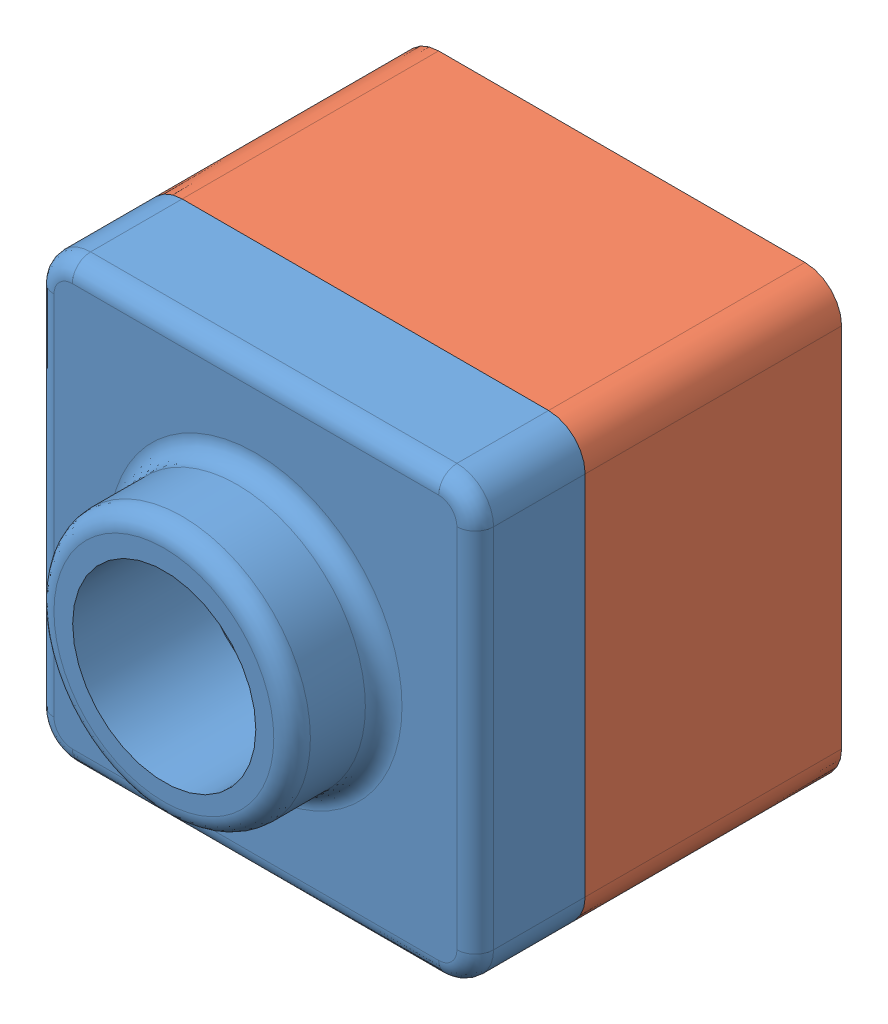
SolidWorks assembly Assembly Marco Gonzalez, configuration Default. Lengths in mm.
Overall size (120 120 125).
2 component instances, 2 part files, 1 mates.
Components (placement in the parent):
- Tutor1-1: Tutor1 [Default] at (-30.7189 45.5979 143.523) size (120 120 55)
- Tutor2-1: Tutor2 [Default] at (-30.7189 45.5979 73.523) size (120 120 90)
Mates (geometry in assembly coordinates):
- Coincident1: coincident: moEndPointRef_w of Tutor1-1; moEndPointRef_w of Tutor2-1
